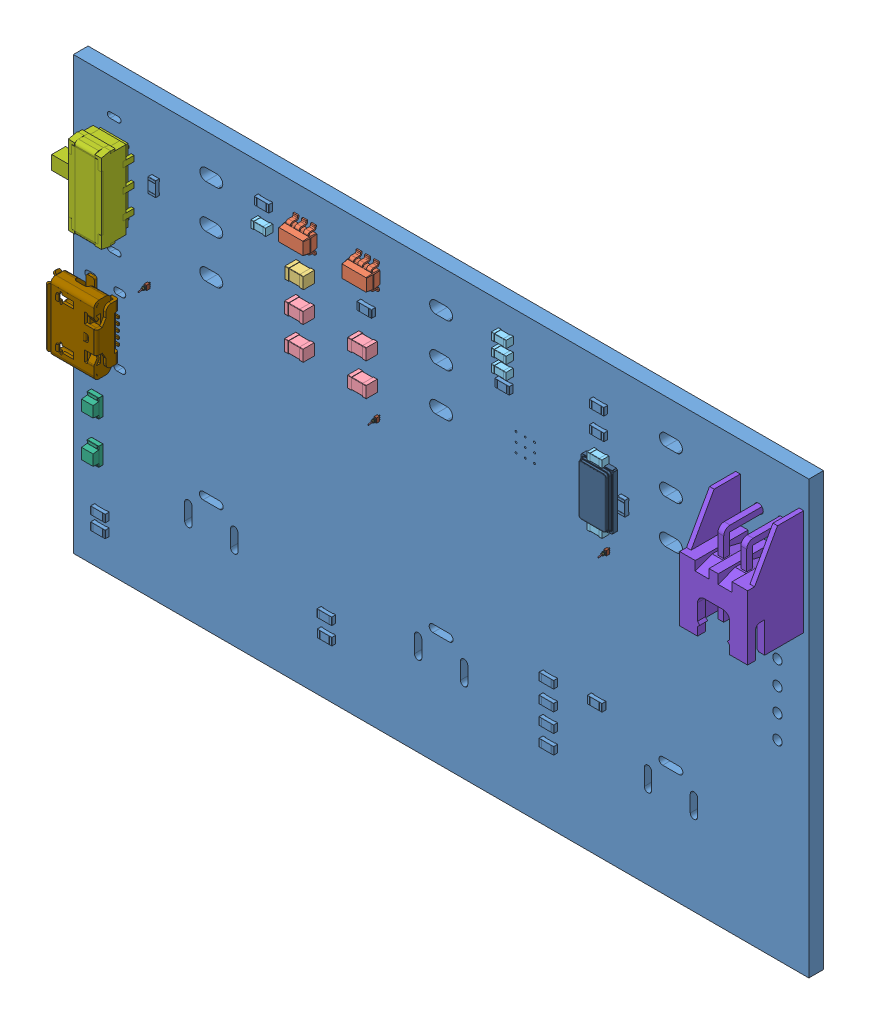
SolidWorks assembly ledTruck.step, configuration Default. Lengths in mm.
Overall size (80.38 47 12.68).
98 component instances, 19 part files, 0 mates.
Components (placement in the parent):
- R_0603_1608Metric.step-1: R_0603_1608Metric.step [Default] at (162.2298 -104.8258 1.65) size (1.6 0.8 0.45)
  - SOLID.step-1: SOLID.step [Default] at origin size (1.6 0.8 0.45)
- SOT-23-5.step-1: SOT-23-5.step [Default] at (130.302 -76.708 1.65) x (0 -1 0) z (0 0 1) size (2.8 2.9 1.55)
  - SOLID-0.step-1: SOLID-0.step [Default] at origin size (2.8 2.9 1.55)
- SOT-23-5.step-2: SOT-23-5.step [Default] at (137.16 -76.708 1.65) x (0 -1 0) z (0 0 1) size (2.8 2.9 1.55)
  - SOLID-0.step-1: SOLID-0.step [Default] at origin size (2.8 2.9 1.55)
- R_0603_1608Metric.step-2: R_0603_1608Metric.step [Default] at (162.433 -79.248 1.65) size (1.6 0.8 0.45)
  - SOLID.step-1: SOLID.step [Default] at origin size (1.6 0.8 0.45)
- R_0603_1608Metric.step-3: R_0603_1608Metric.step [Default] at (162.433 -76.835 1.65) x (-1 0 0) z (0 0 1) size (1.6 0.8 0.45)
  - SOLID.step-1: SOLID.step [Default] at origin size (1.6 0.8 0.45)
- R_0603_1608Metric.step-4: R_0603_1608Metric.step [Default] at (108.1929 -114.012 1.65) size (1.6 0.8 0.45)
  - SOLID.step-1: SOLID.step [Default] at origin size (1.6 0.8 0.45)
- R_0603_1608Metric.step-5: R_0603_1608Metric.step [Default] at (108.1929 -115.512 1.65) size (1.6 0.8 0.45)
  - SOLID.step-1: SOLID.step [Default] at origin size (1.6 0.8 0.45)
- R_0603_1608Metric.step-6: R_0603_1608Metric.step [Default] at (152.146 -80.01 1.65) size (1.6 0.8 0.45)
  - SOLID.step-1: SOLID.step [Default] at origin size (1.6 0.8 0.45)
- R_0603_1608Metric.step-7: R_0603_1608Metric.step [Default] at (165.1 -84.836 1.65) x (0 1 0) z (0 0 1) size (1.6 0.8 0.45)
  - SOLID.step-1: SOLID.step [Default] at origin size (1.6 0.8 0.45)
- R_0603_1608Metric.step-8: R_0603_1608Metric.step [Default] at (137.16 -80.264 1.65) x (-1 0 0) z (0 0 1) size (1.6 0.8 0.45)
  - SOLID.step-1: SOLID.step [Default] at origin size (1.6 0.8 0.45)
- R_0603_1608Metric.step-9: R_0603_1608Metric.step [Default] at (156.972 -111.506 1.65) x (-1 0 0) z (0 0 1) size (1.6 0.8 0.45)
  - SOLID.step-1: SOLID.step [Default] at origin size (1.6 0.8 0.45)
- R_0603_1608Metric.step-10: R_0603_1608Metric.step [Default] at (156.972 -107.442 1.65) size (1.6 0.8 0.45)
  - SOLID.step-1: SOLID.step [Default] at origin size (1.6 0.8 0.45)
- R_0603_1608Metric.step-11: R_0603_1608Metric.step [Default] at (132.842 -113.284 1.65) size (1.6 0.8 0.45)
  - SOLID.step-1: SOLID.step [Default] at origin size (1.6 0.8 0.45)
- R_0603_1608Metric.step-12: R_0603_1608Metric.step [Default] at (156.972 -109.474 1.65) x (-1 0 0) z (0 0 1) size (1.6 0.8 0.45)
  - SOLID.step-1: SOLID.step [Default] at origin size (1.6 0.8 0.45)
- R_0603_1608Metric.step-13: R_0603_1608Metric.step [Default] at (156.972 -105.283 1.65) x (-1 0 0) z (0 0 1) size (1.6 0.8 0.45)
  - SOLID.step-1: SOLID.step [Default] at origin size (1.6 0.8 0.45)
- R_0603_1608Metric.step-14: R_0603_1608Metric.step [Default] at (132.828 -111.379 1.65) size (1.6 0.8 0.45)
  - SOLID.step-1: SOLID.step [Default] at origin size (1.6 0.8 0.45)
- L_0805_2012Metric.step-1: L_0805_2012Metric.step [Default] at (130.336 -80.264 1.65) x (-1 0 0) z (0 0 1) size (2 1.25 1.25)
  - SOLID-1.step-1: SOLID-1.step [Default] at origin size (2 1.25 1.25)
- C_0805_2012Metric.step-1: C_0805_2012Metric.step [Default] at (130.302 -87.122 1.65) size (2 1.25 1.25)
  - SOLID-2.step-1: SOLID-2.step [Default] at origin size (2 1.25 1.25)
- C_0603_1608Metric.step-1: C_0603_1608Metric.step [Default] at (152.146 -78.486 1.65) x (-1 0 0) z (0 0 1) size (1.6 0.8 0.8)
  - SOLID-3.step-1: SOLID-3.step [Default] at origin size (1.6 0.8 0.8)
- C_0805_2012Metric.step-2: C_0805_2012Metric.step [Default] at (137.16 -83.566 1.65) size (2 1.25 1.25)
  - SOLID-2.step-1: SOLID-2.step [Default] at origin size (2 1.25 1.25)
- C_0603_1608Metric.step-2: C_0603_1608Metric.step [Default] at (152.146 -76.962 1.65) x (-1 0 0) z (0 0 1) size (1.6 0.8 0.8)
  - SOLID-3.step-1: SOLID-3.step [Default] at origin size (1.6 0.8 0.8)
- C_0603_1608Metric.step-3: C_0603_1608Metric.step [Default] at (152.146 -75.464 1.65) x (-1 0 0) z (0 0 1) size (1.6 0.8 0.8)
  - SOLID-3.step-1: SOLID-3.step [Default] at origin size (1.6 0.8 0.8)
- C_0805_2012Metric.step-3: C_0805_2012Metric.step [Default] at (130.302 -83.566 1.65) size (2 1.25 1.25)
  - SOLID-2.step-1: SOLID-2.step [Default] at origin size (2 1.25 1.25)
- C_0603_1608Metric.step-4: C_0603_1608Metric.step [Default] at (162.56 -81.534 1.65) size (1.6 0.8 0.8)
  - SOLID-3.step-1: SOLID-3.step [Default] at origin size (1.6 0.8 0.8)
- C_0603_1608Metric.step-5: C_0603_1608Metric.step [Default] at (162.56 -88.138 1.65) size (1.6 0.8 0.8)
  - SOLID-3.step-1: SOLID-3.step [Default] at origin size (1.6 0.8 0.8)
- C_0805_2012Metric.step-4: C_0805_2012Metric.step [Default] at (137.16 -87.122 1.65) size (2 1.25 1.25)
  - SOLID-2.step-1: SOLID-2.step [Default] at origin size (2 1.25 1.25)
- R_0603_1608Metric.step-15: R_0603_1608Metric.step [Default] at (125.984 -75.946 1.65) size (1.6 0.8 0.45)
  - SOLID.step-1: SOLID.step [Default] at origin size (1.6 0.8 0.45)
- R_0603_1608Metric.step-16: R_0603_1608Metric.step [Default] at (114.046 -80.264 1.65) x (0 -1 0) z (0 0 1) size (1.6 0.8 0.45)
  - SOLID.step-1: SOLID.step [Default] at origin size (1.6 0.8 0.45)
- LED_0805_2012Metric.step-1: LED_0805_2012Metric.step [Default] at (107.6929 -108.512 1.65) x (0 -1 0) z (0 0 1) size (2 1.25 1.1)
  - SOLID-4.step-1: SOLID-4.step [Default] at origin size (2 1.25 1.1)
- LED_0805_2012Metric.step-2: LED_0805_2012Metric.step [Default] at (107.6929 -103.962 1.65) x (0 -1 0) z (0 0 1) size (2 1.25 1.1)
  - SOLID-4.step-1: SOLID-4.step [Default] at origin size (2 1.25 1.1)
- C_0603_1608Metric.step-6: C_0603_1608Metric.step [Default] at (125.984 -77.978 1.65) x (-1 0 0) z (0 0 1) size (1.6 0.8 0.8)
  - SOLID-3.step-1: SOLID-3.step [Default] at origin size (1.6 0.8 0.8)
- SW_CuK_JS202011AQN_DPDT_Angled.step-1: SW_CuK_JS202011AQN_DPDT_Angled.step [Default] at (111.474 -79.012 1.65) x (0 -1 0) z (0 0 1) size (9 5.6 6.5)
  - SOLID-5.step-1: SOLID-5.step [Default] at origin size (9 5.6 6.5)
- JST_XH_S2B-XH-A_1x02_P2.50mm_Horizontal.step-1: JST_XH_S2B-XH-A_1x02_P2.50mm_Horizontal.step [Default] at (179.578 -78.012 1.65) size (7.4 11.5 9.5)
  - SOLID-6.step-1: SOLID-6.step [Default] at origin size (7.4 11.5 9.5)
- USB_Micro-B_Molex_47346-0001.step-1: USB_Micro-B_Molex_47346-0001.step [Default] at (108.4213 -96.0044 1.65) x (0 -1 0) z (0 0 1) size (7.98 5.42 2.94)
  - SOLID-7.step-1: SOLID-7.step [Default] at origin size (7.98 5.42 2.94)
- Crystal_SMD_0603-4Pin_6.0x3.5mm.step-1: Crystal_SMD_0603-4Pin_6.0x3.5mm.step [Default] at (162.56 -84.856 1.65) x (0 1 0) z (0 0 1) size (6 3.5 1.03)
  - SOLID-8.step-1: SOLID-8.step [Default] at origin size (6 3.5 1.03)
- 7101 ToggleSwitch.step-1: 7101 ToggleSwitch.step [Default] at (121.534 -82.012 10.15) size (0.36 0.5 1.28)
  - SOLID-9.step-1: SOLID-9.step [Default] at origin size (0.28 0.5 0.35)
  - SOLID-10.step-1: SOLID-10.step [Default] at origin size (0.24 0.24 0.35)
  - SOLID-11.step-1: SOLID-11.step [Default] at origin size (0.12 0.21 0.43)
  - SOLID-12.step-1: SOLID-12.step [Default] at origin size (0.36 0.31 0.06)
  - SOLID-13.step-1: SOLID-13.step [Default] at origin size (0.36 0.31 0.06)
  - SOLID-14.step-1: SOLID-14.step [Default] at origin size (0.08 0.03 0.16)
  - SOLID-15.step-1: SOLID-15.step [Default] at origin size (0.08 0.03 0.16)
  - SOLID-16.step-1: SOLID-16.step [Default] at origin size (0.08 0.03 0.16)
- 7101 ToggleSwitch.step-2: 7101 ToggleSwitch.step [Default] at (146.534 -82.012 10.15) size (0.36 0.5 1.28)
  - SOLID-9.step-1: SOLID-9.step [Default] at origin size (0.28 0.5 0.35)
  - SOLID-10.step-1: SOLID-10.step [Default] at origin size (0.24 0.24 0.35)
  - SOLID-11.step-1: SOLID-11.step [Default] at origin size (0.12 0.21 0.43)
  - SOLID-12.step-1: SOLID-12.step [Default] at origin size (0.36 0.31 0.06)
  - SOLID-13.step-1: SOLID-13.step [Default] at origin size (0.36 0.31 0.06)
  - SOLID-14.step-1: SOLID-14.step [Default] at origin size (0.08 0.03 0.16)
  - SOLID-15.step-1: SOLID-15.step [Default] at origin size (0.08 0.03 0.16)
  - SOLID-16.step-1: SOLID-16.step [Default] at origin size (0.08 0.03 0.16)
- 7101 ToggleSwitch.step-3: 7101 ToggleSwitch.step [Default] at (171.534 -82.012 10.15) size (0.36 0.5 1.28)
  - SOLID-9.step-1: SOLID-9.step [Default] at origin size (0.28 0.5 0.35)
  - SOLID-10.step-1: SOLID-10.step [Default] at origin size (0.24 0.24 0.35)
  - SOLID-11.step-1: SOLID-11.step [Default] at origin size (0.12 0.21 0.43)
  - SOLID-12.step-1: SOLID-12.step [Default] at origin size (0.36 0.31 0.06)
  - SOLID-13.step-1: SOLID-13.step [Default] at origin size (0.36 0.31 0.06)
  - SOLID-14.step-1: SOLID-14.step [Default] at origin size (0.08 0.03 0.16)
  - SOLID-15.step-1: SOLID-15.step [Default] at origin size (0.08 0.03 0.16)
  - SOLID-16.step-1: SOLID-16.step [Default] at origin size (0.08 0.03 0.16)
- COMPOUND.step-1: COMPOUND.step [Default] at origin size (80 47 1.6)
